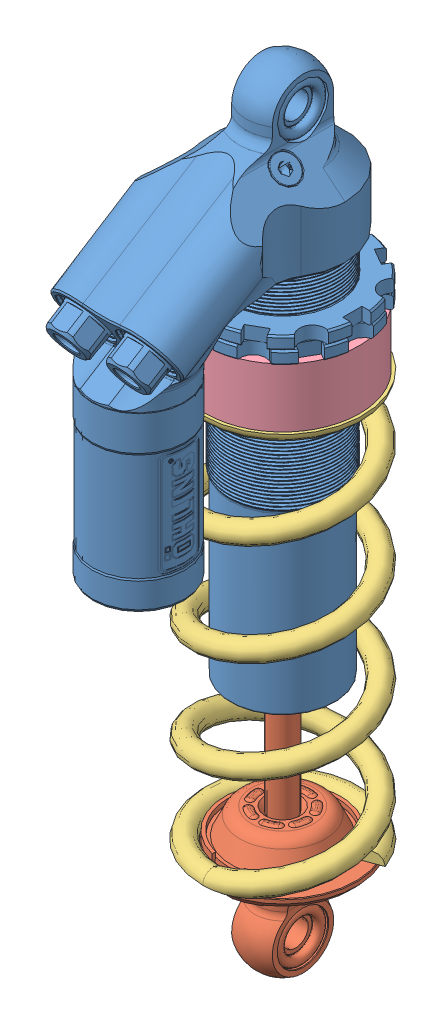
SolidWorks assembly Rear Shock Assembly, configuration Default. Lengths in mm.
Overall size (49.99 246.92 86.39).
4 component instances, 4 part files, 7 mates.
Components (placement in the parent):
- Ohlin Top-1: Ohlin Top [Default] at (44.421 183.8576 102.443) size (49.14 167 85.96)
- Ohlin Bottom-1: Ohlin Bottom [Default] at (44.421 -40.0644 102.443) size (46 142.31 45.56)
- QM Spring-1: QM Spring [Default] at (44.421 -16.5644 102.443) size (49.99 140.12 51.62)
- Shock Spacer Rear-1: Shock Spacer Rear [Default] at (44.421 110.4356 102.443) size (48 18.42 48)
Mates (geometry in assembly coordinates):
- Concentric1: concentric: cylinder of Ohlin Top-1 through (44.421 28.3576 102.443) axis (0 -1 0) radius 16.3; cylinder of Ohlin Bottom-1 through (44.421 -39.2227 102.443) axis (0 -1 0) radius 3.9935
- Coincident1: coincident: plane of Ohlin Top-1 through (50.771 177.3576 78.4361) normal (-1 0 0); plane of Ohlin Bottom-1 through (50.771 -59.3106 113.943) normal (1 0 0)
- Concentric2: concentric: cylinder of Ohlin Top-1 through (44.421 28.3576 102.443) axis (0 -1 0) radius 16.3; circle of QM Spring-1
- Coincident3: coincident: plane of Ohlin Bottom-1 through (67.421 -26.2227 102.443) normal (0 1 0); plane of QM Spring-1 through (-4.146 -26.2227 77.446) normal (0 -1 0)
- Concentric3: concentric: cylinder of Ohlin Top-1 through (44.421 116.8576 102.443) axis (0 -1 0) radius 18.1; cylinder of Shock Spacer Rear-1 through (42.8071 125.7593 101.5678) axis (0 -1 0) radius 18.415
- Coincident4: coincident: plane of Ohlin Top-1 through (69.171 128.8576 102.443) normal (0 -1 0); plane of Shock Spacer Rear-1 through (42.8071 125.7593 101.5678) normal (0 1 0)
- Coincident5: coincident: plane of QM Spring-1 through (-4.146 110.4356 77.446) normal (0 1 0); plane of Shock Spacer Rear-1 through (44.421 110.4356 102.443) normal (0 -1 0)
